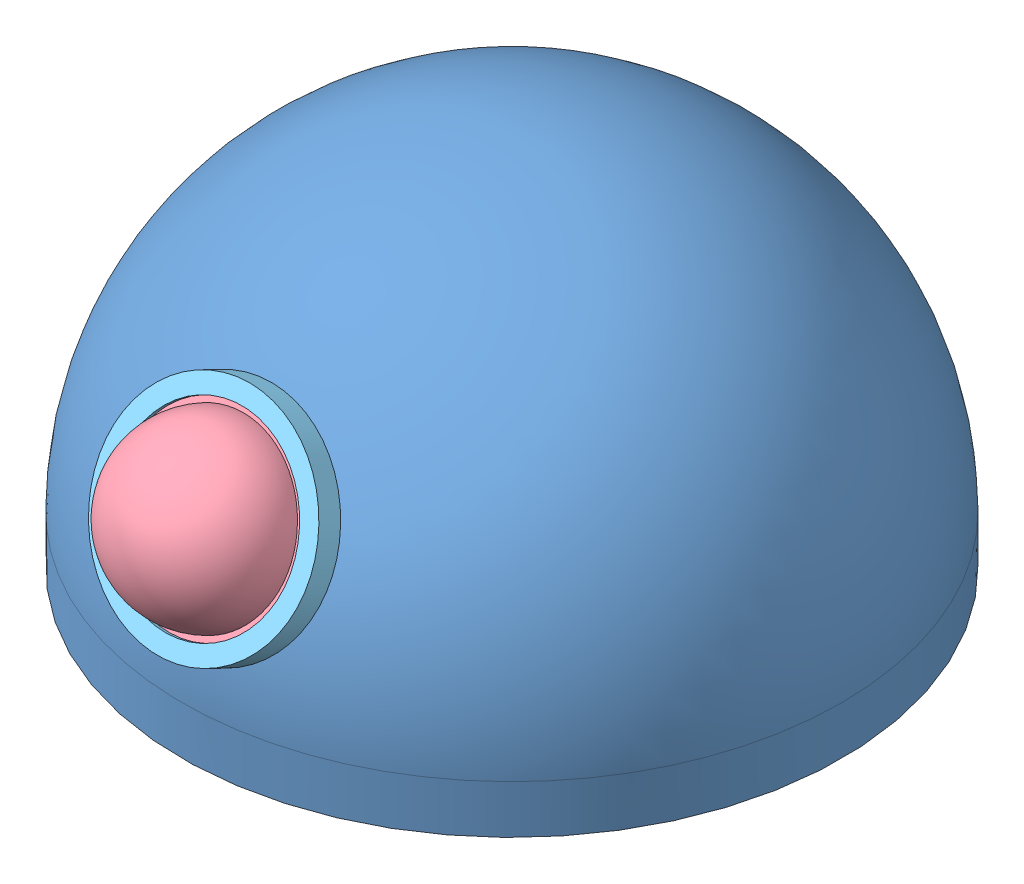
SolidWorks assembly Assem1, configuration Default. Lengths in mm.
Overall size (300 196.37 346.85).
12 component instances, 6 part files, 17 mates.
Components (placement in the parent):
- BB-8Head-1: BB-8Head [Default] at (-60.3491 175.3135 319.9466) size (300 195.24 308.7)
- BB-8HeadBottom-1: BB-8HeadBottom [Default] at (-60.3491 -219.631 319.9466) size (200.31 22.07 200.31)
- Ball Bearing-1: Ball Bearing [Default] at (-17.9227 146.0076 277.5202) size (19 19 19)
- Ball Bearing-2: Ball Bearing [Default] at (-102.7755 146.0076 362.373) size (19 19 19)
- Ball Bearing-3: Ball Bearing [Default] at (-102.7755 146.0076 277.5202) size (19 19 19)
- Ball Bearing-4: Ball Bearing [Default] at (-17.9227 146.0076 362.373) size (19 19 19)
- BB-8Eye-1: BB-8Eye [Default] at (-60.3491 241.9765 458.4006) x (0 -0.433816 -0.901002) z (0.901002 -0.390869 0.188196) size (39.5 85 85)
- BB-8EyeCap-1: BB-8EyeCap [Default] at (-60.3491 238.0721 450.2915) x (0 -0.433816 -0.901002) z (0.650455 -0.684351 0.329502) size (11.02 96.2 96.2)
- Ball-Bearing-Cap-1: Ball-Bearing-Cap [Default] at (-17.9227 146.0076 277.5202) x (0.917432 -0.390978 0.073862) z (-0.006157 0.171661 0.985137) size (24.66 15.93 24.9)
- Ball-Bearing-Cap-2: Ball-Bearing-Cap [Default] at (-102.7755 146.0076 277.5202) x (0.996884 -0.064375 0.045583) z (-0.034435 0.164736 0.985736) size (24.66 15.93 24.9)
- Ball-Bearing-Cap-3: Ball-Bearing-Cap [Default] at (-102.7755 146.0076 362.373) x (0.996884 -0.064375 -0.045583) z (0.034435 -0.164736 0.985736) size (24.66 15.93 24.9)
- Ball-Bearing-Cap-4: Ball-Bearing-Cap [Default] at (-17.9227 146.0076 362.373) x (0.917432 -0.390978 -0.073862) z (0.006157 -0.171661 0.985137) size (24.66 15.93 24.9)
Mates (geometry in assembly coordinates):
- Concentric1: concentric: sphere of BB-8HeadBottom-1; sphere of Ball Bearing-4
- Concentric2: concentric: sphere of BB-8HeadBottom-1; sphere of Ball Bearing-2
- Concentric4: concentric: sphere of BB-8HeadBottom-1; sphere of Ball Bearing-1
- Concentric5: concentric: sphere of BB-8HeadBottom-1; sphere of Ball Bearing-3
- Concentric6: concentric aligned: circle of BB-8HeadBottom-1; circle of Ball-Bearing-Cap-1
- Coincident1: coincident anti-aligned: plane of BB-8HeadBottom-1 through (1.7861 139.1817 257.8114) normal (0.168199 0.971297 -0.168199); plane of Ball-Bearing-Cap-1 through (-17.9227 146.0076 277.5202) normal (-0.168199 -0.971297 0.168199)
- Concentric7: concentric aligned: circle of BB-8HeadBottom-1; circle of Ball-Bearing-Cap-2
- Coincident2: coincident anti-aligned: plane of BB-8HeadBottom-1 through (-122.4843 139.1817 257.8114) normal (-0.168199 0.971297 -0.168199); plane of Ball-Bearing-Cap-2 through (-102.7755 146.0076 277.5202) normal (0.168199 -0.971297 0.168199)
- Concentric8: concentric aligned: circle of BB-8HeadBottom-1; circle of Ball-Bearing-Cap-3
- Coincident3: coincident anti-aligned: plane of BB-8HeadBottom-1 through (-122.4843 139.1817 382.0819) normal (-0.168199 0.971297 0.168199); plane of Ball-Bearing-Cap-3 through (-102.7755 146.0076 362.373) normal (0.168199 -0.971297 -0.168199)
- Concentric9: concentric aligned: circle of BB-8HeadBottom-1; circle of Ball-Bearing-Cap-4
- Coincident4: coincident anti-aligned: plane of BB-8HeadBottom-1 through (1.7861 139.1817 382.0819) normal (0.168199 0.971297 0.168199); plane of Ball-Bearing-Cap-4 through (-17.9227 146.0076 362.373) normal (-0.168199 -0.971297 -0.168199)
- Coincident5: coincident anti-aligned: circle of BB-8Head-1; circle of BB-8HeadBottom-1
- Coincident7: coincident: plane of BB-8Head-1 through (-60.3491 241.1089 456.5986) normal (0 0.433816 0.901002); plane of BB-8Eye-1 through (-60.3491 241.1089 456.5986) normal (0 -0.433816 -0.901002)
- Concentric10: concentric aligned: circle of BB-8Head-1; circle of BB-8Eye-1
- Concentric11: concentric: circle of BB-8Eye-1; circle of BB-8EyeCap-1
- Coincident8: coincident anti-aligned: plane of BB-8Eye-1 through (-60.3491 241.9765 458.4006) normal (0 0.433816 0.901002); plane of BB-8EyeCap-1 through (-60.3491 241.9765 458.4006) normal (0 -0.433816 -0.901002)
